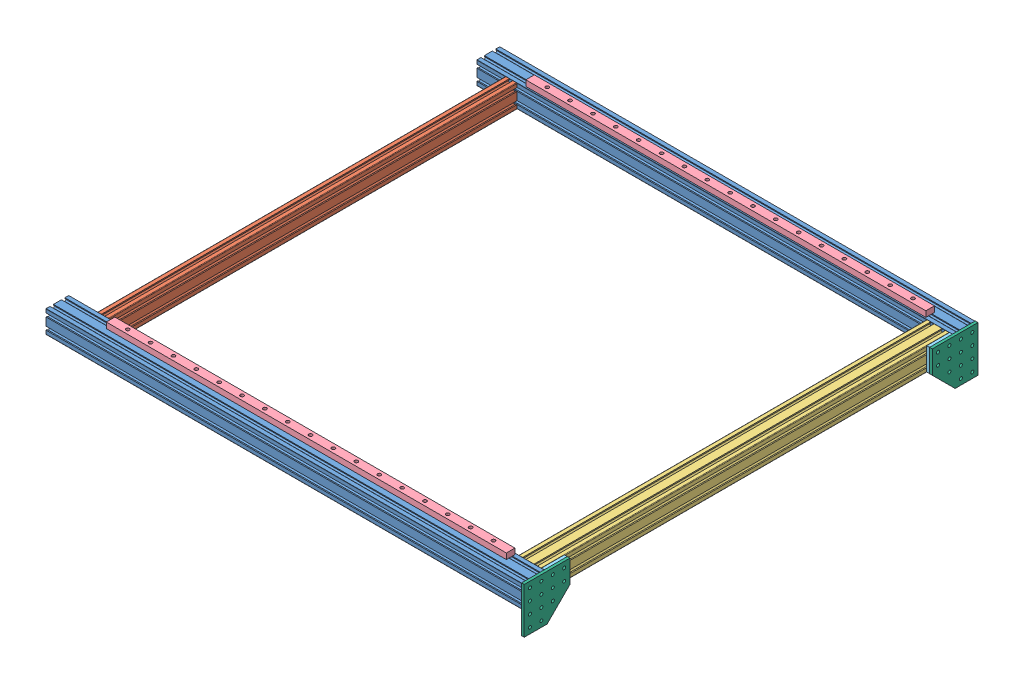
SolidWorks assembly upper_frame, configuration Default. Lengths in mm.
Overall size (836.76 89.6 794).
12 component instances, 7 part files, 33 mates.
Components (placement in the parent):
- MISUMI_HFSP5-4040-832.0_Aluminum extrusion-1: MISUMI_HFSP5-4040-832.0_Aluminum extrusion [Default] at (-50.5033 0 0.2656) size (832 39.2 40)
- MISUMI_HFSP5-4040-832.0_Aluminum extrusion-2: MISUMI_HFSP5-4040-832.0_Aluminum extrusion [Default] at (-50.5033 0 -753.7344) size (832 39.2 40)
- MISUMI_NFS5-2040-714.0_Aluminum extrusion-1: MISUMI_NFS5-2040-714.0_Aluminum extrusion [Default] at (9.4967 -0.4 -19.7344) x (0 0 -1) z (1 0 0) size (714 40 20)
- MISUMI_HFS5-4040-714.0_Aluminum extrusion-1: MISUMI_HFS5-4040-714.0_Aluminum extrusion [Default] at (756.4967 -0.4 -19.7344) x (0 0 -1) z (1 0 0) size (714 40 40)
- upper_front_mount_plate-1: upper_front_mount_plate [right] at (781.4967 -60 -693.7344) x (0 0 -1) z (1 0 0) size (80 80 9.76) (hidden)
- upper_front_mount_plate-3: upper_front_mount_plate [left] at (781.4967 -60 -59.7344) x (0 0 1) z (-1 0 0) size (80 80 9.76) (hidden)
- MGN15_rail_700-4: MGN15_rail_700 [Default] at (32.4967 19.6 -736.2344) x (0 0 -1) z (1 0 0) size (15 10 700)
- MGN15_rail_700-5: MGN15_rail_700 [Default] at (32.4967 19.6 -2.2344) x (0 0 -1) z (1 0 0) size (15 10 700)
- front_spacer_plate-1: front_spacer_plate [Default] at (776.4967 -20 -19.7344) x (0 0 -1) z (1 0 0) size (40 40 5)
- 4040_mount_plate-1: 4040_mount_plate [Default] at (781.4967 -60 20.2656) x (0 0 -1) z (1 0 0) size (80 80 4.76)
- front_spacer_plate-2: front_spacer_plate [Default] at (776.4967 20 -693.7344) x (0 -1 0) z (1 0 0) size (40 40 5)
- 4040_mount_plate-2: 4040_mount_plate [Default] at (781.4967 20 -693.7344) x (0 -1 0) z (1 0 0) size (80 80 4.76)
Mates (geometry in assembly coordinates):
- Coincident4: coincident aligned: plane of MISUMI_HFSP5-4040-832.0_Aluminum extrusion-1 through (781.4967 19.6 -19.5344) normal (0 1 0); plane of MISUMI_NFS5-2040-714.0_Aluminum extrusion-1 through (12.4967 19.6 -733.7344) normal (0 1 0)
- Coincident6: coincident anti-aligned: plane of MISUMI_HFSP5-4040-832.0_Aluminum extrusion-1 through (781.4967 13 -19.7344) normal (0 0 -1); plane of MISUMI_NFS5-2040-714.0_Aluminum extrusion-1 through (18.4967 -19.4 -19.7344) normal (0 0 1)
- Coincident59: coincident aligned: plane of MISUMI_HFSP5-4040-832.0_Aluminum extrusion-1 through (781.4967 19.6 -6.7344) normal (0 1 0); plane of MISUMI_HFS5-4040-714.0_Aluminum extrusion-1 through (749.4967 19.6 -733.7344) normal (0 1 0)
- Coincident60: coincident anti-aligned: plane of MISUMI_HFSP5-4040-832.0_Aluminum extrusion-1 through (781.4967 -7 -19.7344) normal (0 0 -1); plane of MISUMI_HFS5-4040-714.0_Aluminum extrusion-1 through (775.4967 18.6 -19.7344) normal (0 0 1)
- Coincident10: coincident aligned: plane of MISUMI_NFS5-2040-714.0_Aluminum extrusion-1 through (12.4967 19.6 -733.7344) normal (0 1 0); plane of MISUMI_HFSP5-4040-832.0_Aluminum extrusion-2 through (781.4967 19.6 -740.7344) normal (0 1 0)
- Coincident11: coincident anti-aligned: plane of MISUMI_NFS5-2040-714.0_Aluminum extrusion-1 through (18.4967 -19.4 -733.7344) normal (0 0 -1); plane of MISUMI_HFSP5-4040-832.0_Aluminum extrusion-2 through (781.4967 19 -733.7344) normal (0 0 1)
- Distance1: distance = 50 mm aligned: plane of MISUMI_HFSP5-4040-832.0_Aluminum extrusion-1 through (-50.5033 19 19.2656) normal (-1 0 0); plane of MISUMI_NFS5-2040-714.0_Aluminum extrusion-1 through (-0.5033 -7.4 -733.7344) normal (-1 0 0)
- Coincident64: coincident aligned: plane of MISUMI_HFSP5-4040-832.0_Aluminum extrusion-2 through (781.4967 19.6 -760.7344) normal (0 1 0); plane of MISUMI_HFS5-4040-714.0_Aluminum extrusion-1 through (749.4967 19.6 -733.7344) normal (0 1 0)
- Coincident65: coincident anti-aligned: plane of MISUMI_HFSP5-4040-832.0_Aluminum extrusion-2 through (781.4967 7 -733.7344) normal (0 0 1); plane of MISUMI_HFS5-4040-714.0_Aluminum extrusion-1 through (775.4967 18.6 -733.7344) normal (0 0 -1)
- Coincident990: coincident anti-aligned: plane of MISUMI_HFS5-4040-714.0_Aluminum extrusion-1 through (776.4967 6.6 -733.7344) normal (1 0 0); plane of upper_front_mount_plate-1 through (776.4967 -60 -693.7344) normal (-1 0 0)
- Coincident991: coincident anti-aligned: plane of MISUMI_HFSP5-4040-832.0_Aluminum extrusion-2 through (781.4967 19 -734.7344) normal (1 0 0); plane of upper_front_mount_plate-1 through (781.4967 -60 -693.7344) normal (-1 0 0)
- Concentric1: concentric aligned: circle of MISUMI_HFSP5-4040-832.0_Aluminum extrusion-2; circle of upper_front_mount_plate-1
- Concentric2: concentric aligned: circle of MISUMI_HFSP5-4040-832.0_Aluminum extrusion-2; circle of upper_front_mount_plate-1
- Coincident992: coincident anti-aligned: plane of MISUMI_HFS5-4040-714.0_Aluminum extrusion-1 through (776.4967 6.6 -733.7344) normal (1 0 0); plane of upper_front_mount_plate-3 through (776.4967 -60 -59.7344) normal (-1 0 0)
- Coincident993: coincident anti-aligned: plane of MISUMI_HFSP5-4040-832.0_Aluminum extrusion-1 through (781.4967 19 19.2656) normal (1 0 0); plane of upper_front_mount_plate-3 through (781.4967 -60 -59.7344) normal (-1 0 0)
- Concentric3: concentric anti-aligned: circle of MISUMI_HFSP5-4040-832.0_Aluminum extrusion-1; circle of upper_front_mount_plate-3
- Concentric4: concentric anti-aligned: circle of MISUMI_HFSP5-4040-832.0_Aluminum extrusion-1; circle of upper_front_mount_plate-3
- Coincident958: coincident anti-aligned: plane of MISUMI_HFSP5-4040-832.0_Aluminum extrusion-2 through (781.4967 19.6 -760.7344) normal (0 1 0); plane of MGN15_rail_700-4 through (732.4967 19.6 -736.2344) normal (0 -1 0)
- Distance15: distance = 2.5 mm aligned: plane of MISUMI_HFSP5-4040-832.0_Aluminum extrusion-2 through (781.4967 7 -733.7344) normal (0 0 1); plane of MGN15_rail_700-4 through (732.4967 19.6 -736.2344) normal (0 0 1)
- Coincident964: coincident anti-aligned: plane of MISUMI_HFSP5-4040-832.0_Aluminum extrusion-1 through (781.4967 19.6 -6.7344) normal (0 1 0); plane of MGN15_rail_700-5 through (732.4967 19.6 -2.2344) normal (0 -1 0)
- Distance18: distance = 2.5 mm aligned: plane of MISUMI_HFSP5-4040-832.0_Aluminum extrusion-1 through (781.4967 -7 -19.7344) normal (0 0 -1); plane of MGN15_rail_700-5 through (732.4967 19.6 -17.2344) normal (0 0 -1)
- Coincident994: coincident anti-aligned: plane of MISUMI_HFS5-4040-714.0_Aluminum extrusion-1 through (776.4967 6.6 -733.7344) normal (1 0 0); plane of front_spacer_plate-1 through (776.4967 -20 -19.7344) normal (-1 0 0)
- Concentric5: concentric aligned: cylinder of front_spacer_plate-1 through (781.4967 10 -49.7344) axis (1 0 0) radius 2.9; cylinder of 4040_mount_plate-1 through (786.2592 10 -49.7344) axis (1 0 0) radius 2.65
- Concentric6: concentric aligned: cylinder of front_spacer_plate-1 through (781.4967 -10 -29.7344) axis (1 0 0) radius 2.9; cylinder of 4040_mount_plate-1 through (786.2592 -10 -29.7344) axis (1 0 0) radius 2.65
- Coincident995: coincident anti-aligned: plane of MISUMI_HFSP5-4040-832.0_Aluminum extrusion-1 through (781.4967 19 19.2656) normal (1 0 0); plane of 4040_mount_plate-1 through (781.4967 -60 20.2656) normal (-1 0 0)
- Concentric7: concentric anti-aligned: cylinder of MISUMI_HFSP5-4040-832.0_Aluminum extrusion-1 through (781.4967 10 10.2656) axis (-1 0 0) radius 2.1; cylinder of 4040_mount_plate-1 through (786.2592 10 10.2656) axis (1 0 0) radius 2.65
- Concentric8: concentric anti-aligned: cylinder of MISUMI_HFSP5-4040-832.0_Aluminum extrusion-1 through (781.4967 -10 -9.7344) axis (-1 0 0) radius 2.1; cylinder of 4040_mount_plate-1 through (786.2592 -10 -9.7344) axis (1 0 0) radius 2.65
- Coincident996: coincident anti-aligned: plane of MISUMI_HFS5-4040-714.0_Aluminum extrusion-1 through (776.4967 6.6 -733.7344) normal (1 0 0); plane of front_spacer_plate-2 through (776.4967 20 -693.7344) normal (-1 0 0)
- Coincident997: coincident anti-aligned: plane of front_spacer_plate-2 through (781.4967 20 -693.7344) normal (1 0 0); plane of 4040_mount_plate-2 through (781.4967 20 -693.7344) normal (-1 0 0)
- Concentric11: concentric aligned: cylinder of front_spacer_plate-2 through (781.4967 10 -703.7344) axis (1 0 0) radius 2.9; cylinder of 4040_mount_plate-2 through (786.2592 10 -703.7344) axis (1 0 0) radius 2.65
- Concentric12: concentric aligned: cylinder of front_spacer_plate-2 through (781.4967 -10 -723.7344) axis (1 0 0) radius 2.9; cylinder of 4040_mount_plate-2 through (786.2592 -10 -723.7344) axis (1 0 0) radius 2.65
- Concentric13: concentric anti-aligned: cylinder of MISUMI_HFSP5-4040-832.0_Aluminum extrusion-2 through (781.4967 10 -743.7344) axis (-1 0 0) radius 2.1; cylinder of 4040_mount_plate-2 through (786.2592 10 -743.7344) axis (1 0 0) radius 2.65
- Concentric14: concentric anti-aligned: cylinder of MISUMI_HFSP5-4040-832.0_Aluminum extrusion-2 through (781.4967 -10 -763.7344) axis (-1 0 0) radius 2.1; cylinder of 4040_mount_plate-2 through (786.2592 -10 -763.7344) axis (1 0 0) radius 2.65
